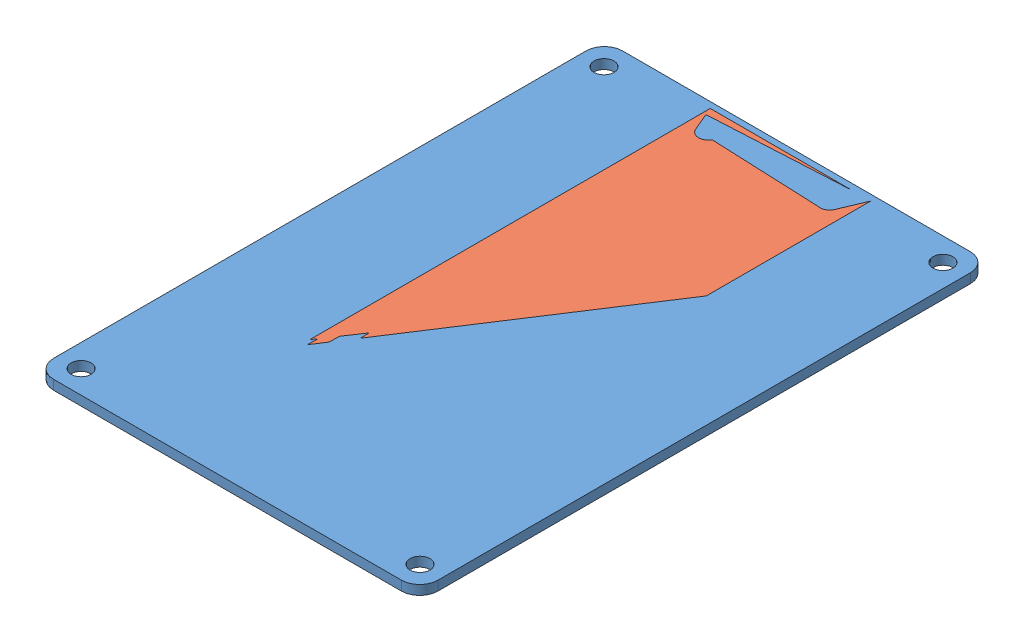
SolidWorks assembly Assem1, configuration Default. Lengths in mm.
Overall size (63.5 1.57 94).
2 component instances, 2 part files, 3 mates.
Components (placement in the parent):
- stock-1: stock [Default] at origin size (63.5 1.57 94)
- pcb-1: pcb [Default] at origin size (26.5 1.57 92)
Mates (geometry in assembly coordinates):
- Width1: width: plane of stock-1 through (31.75 1.57 -47) normal (1 0 0); plane of stock-1 through (-31.75 1.57 -47) normal (-1 0 0); plane of pcb-1 through (13.25 1.57 -43.6133) normal (1 0 0); plane of pcb-1 through (-13.25 1.57 -43.6133) normal (-1 0 0)
- Coincident2: coincident: plane of stock-1 through (0 1.57 0) normal (0 1 0); plane of pcb-1 through (0 1.57 2.3867) normal (0 1 0)
- Width2: width aligned: plane of stock-1 through (-31.75 1.57 -47) normal (0 0 -1); plane of stock-1 through (-31.75 1.57 47) normal (0 0 1); plane of pcb-1 through (13.25 1.57 -46) normal (0 0 -1); plane of pcb-1 through (13.25 1.57 46) normal (0 0 1)
